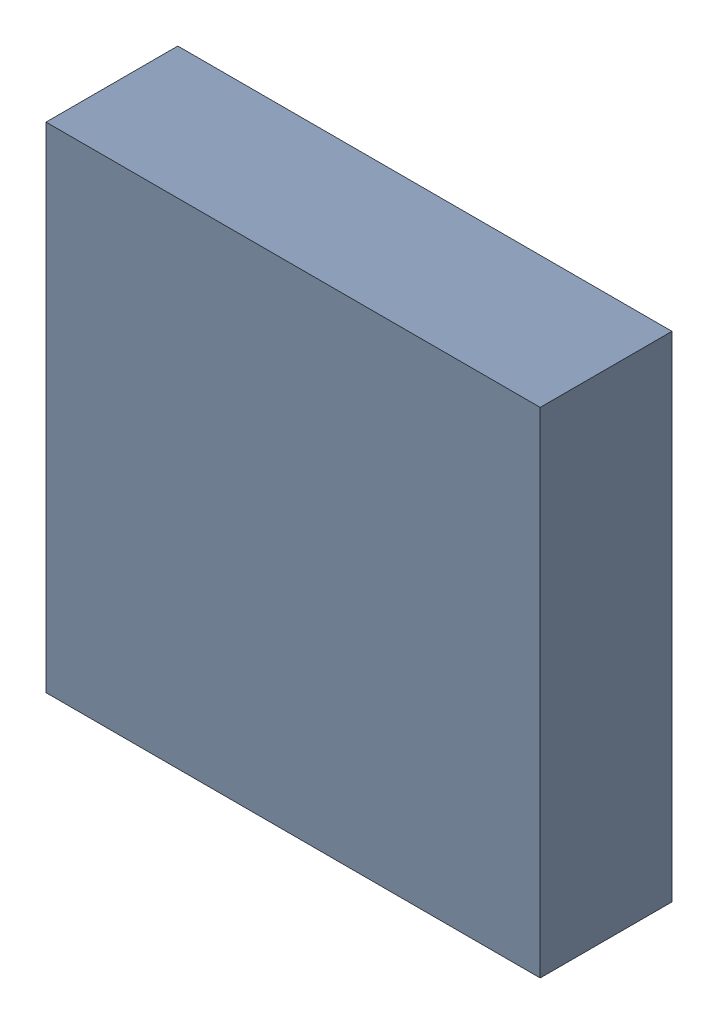
SolidWorks assembly U17, configuration Default. Lengths in mm.
Overall size (3 3 0.8).
2 component instances, 1 part files, 0 mates.
Components (placement in the parent):
- 836753776-1: 836753776 [Default] at (127.05 56.45 0) size (3 3 0.8)
  - Extruded_21-1: Extruded_21 [Default] at origin size (3 3 0.8)
